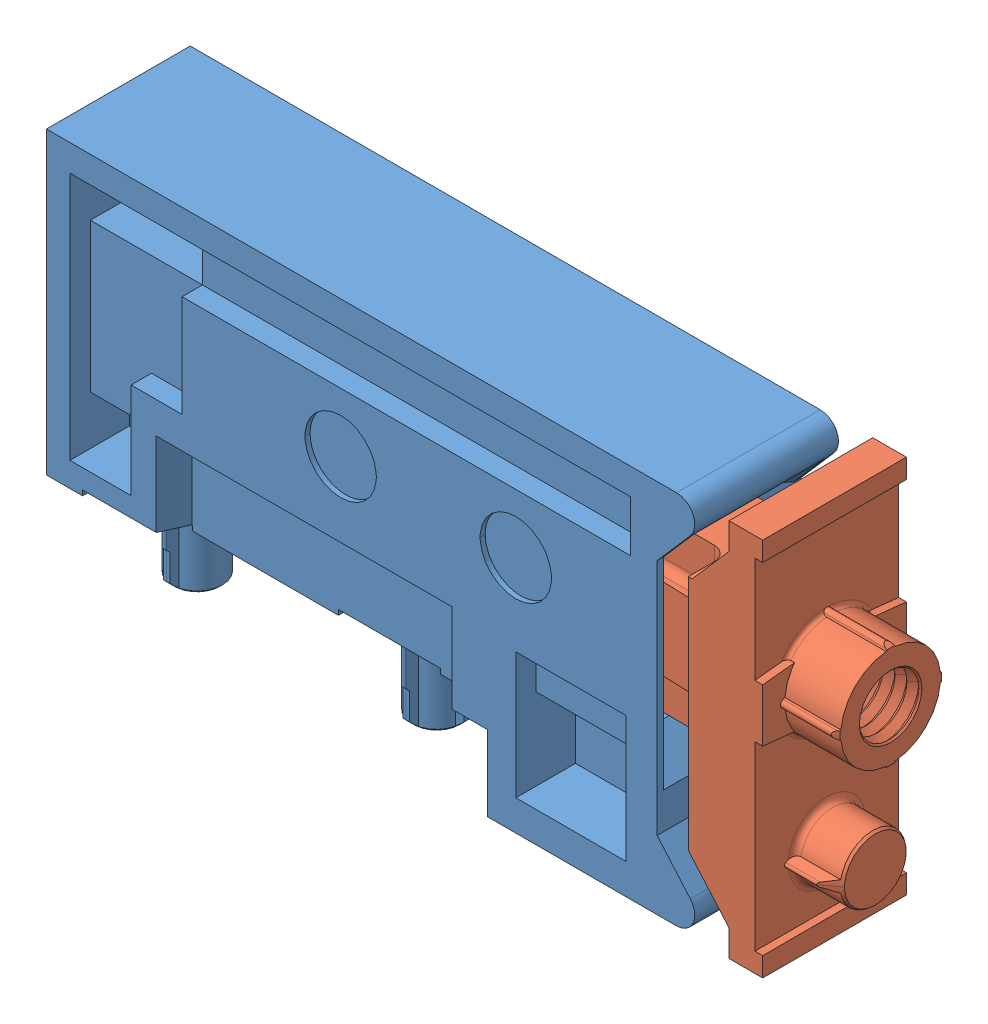
SolidWorks assembly Assem104, configuration Default. Lengths in mm.
Overall size (37.88 18.8 7.05).
2 component instances, 2 part files, 2 mates.
Components (placement in the parent):
- EGBF-RA-20-1: EGBF-RA-20 [Default] at origin size (31.8 18.7 7.05)
- EGBM-VT-2-25.3-20-1: EGBM-VT-2-25.3-20 [Default] at (20.1546 0 0) x (0 -1 0) z (0 0 -1) size (18.6 28.05 7.05)
Mates (geometry in assembly coordinates):
- Width1: width: plane of EGBF-RA-20-1 through (-7.225 -4.3 1.7) normal (0 1 0); plane of EGBF-RA-20-1 through (-7.225 4.3 1.7) normal (0 -1 0); plane of EGBM-VT-2-25.3-20-1 through (-5.1454 -4.175 1.55) normal (0 -1 0); plane of EGBM-VT-2-25.3-20-1 through (16.7008 4.175 -3.525) normal (0 1 0)
- Width2: width: plane of EGBF-RA-20-1 through (-7.225 4.3 1.7) normal (0 0 -1); plane of EGBF-RA-20-1 through (-7.225 4.3 -1.7) normal (0 0 1); plane of EGBM-VT-2-25.3-20-1 through (-5.1454 4.175 1.55) normal (0 0 1); plane of EGBM-VT-2-25.3-20-1 through (-5.1454 4.175 -1.55) normal (0 0 -1)
